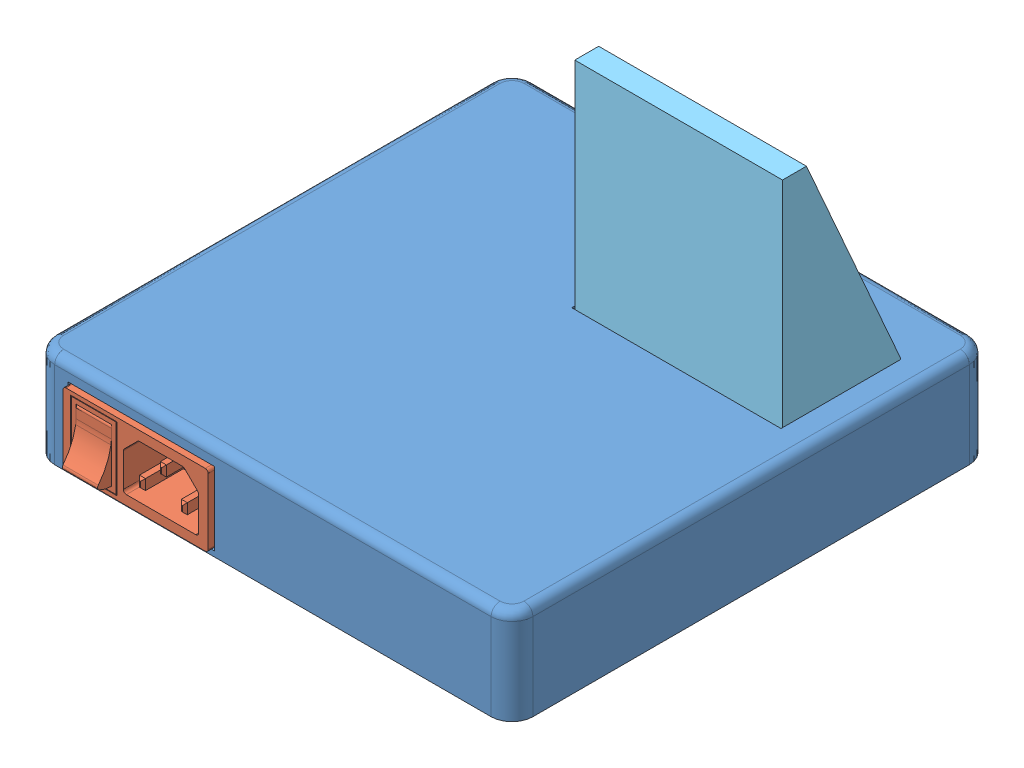
SolidWorks assembly heatplate_case, configuration Default. Lengths in mm.
Overall size (160 104.21 166.72).
6 component instances, 6 part files, 12 mates.
Components (placement in the parent):
- case-2: case [Default] at (15.3311 -15.6956 -180.8) size (160 32 160)
- IEC-socket+switch-2: IEC-socket+switch [Default] at (-13.1856 2.06 -57.9) x (1 0 0) z (0 0 -1) size (48.6 24 24.72)
- SSR40-2: SSR40 [Default] at (-9.1885 -15.6956 -131.0539) size (60 23 46)
- PSU_5V-3: PSU_5V [Default] at (65.283 -13.6956 -117.2434) size (74.5 28 51)
- case-display-holder-1: case-display-holder [Default] at (69.23 16.7044 -176.9583) x (1 0 0) z (0 0 -1) size (75.5 78.76 60)
- LCD-1: LCD [Default] at (81.3746 13.3913 -195.3412) x (-1 0 0) z (0 0.403846 -0.914827) size (63.15 82.2 5.6)
Mates (geometry in assembly coordinates):
- Coincident1: coincident anti-aligned: plane of case-2 through (95.2644 14.3044 -61.5) normal (0 0 1); plane of IEC-socket+switch-2 through (-2.2597 -12.4456 -61.5) normal (0 0 -1)
- Coincident3: coincident anti-aligned: plane of case-2 through (-50.2597 10.5544 -117.7837) normal (0 -1 0); plane of IEC-socket+switch-2 through (-48.8597 10.5544 -61.5) normal (0 1 0)
- Coincident4: coincident anti-aligned: plane of case-2 through (-1.2597 10.5544 -117.7837) normal (-1 0 0); plane of IEC-socket+switch-2 through (-1.2597 -12.4456 -61.5) normal (1 0 0)
- Coincident5: coincident aligned: plane of case-2 through (15.3311 -15.6956 -180.8) normal (0 -1 0); plane of PSU_5V-2 through (1656.1127 -15.6956 878.9867) normal (0 -1 0)
- Coincident6: coincident aligned: plane of case-2 through (15.3311 -15.6956 -180.8) normal (0 -1 0); plane of SSR40-2 through (-9.1885 -15.6956 -131.0539) normal (0 -1 0)
- Coincident8: coincident anti-aligned: plane of case-2 through (15.3311 14.3044 -180.8) normal (0 -1 0); plane of PSU_5V-3 through (65.283 14.3044 -117.2434) normal (0 1 0)
- Coincident11: coincident anti-aligned: plane of case-2 through (15.3311 11.3044 -180.8) normal (0 -1 0); plane of case-display-holder-1 through (69.23 11.3044 -176.9583) normal (0 1 0)
- Coincident13: coincident anti-aligned: plane of case-2 through (88.2644 -15.6966 -200) normal (-1 0 0); plane of case-display-holder-1 through (88.2644 15.7044 -160.5) normal (1 0 0)
- Coincident14: coincident anti-aligned: plane of case-2 through (18.2644 -15.6966 -200) normal (0 0 1); plane of case-display-holder-1 through (18.7644 15.7044 -200) normal (0 0 -1)
- Coincident15: coincident aligned: plane of case-display-holder-1 through (4.7046 88.0609 -168.5) normal (0 0.403846 -0.914827); plane of LCD-1 through (81.3746 15.6528 -200.4642) normal (0 0.403846 -0.914827)
- Parallel2: parallel anti-aligned: plane of case-display-holder-1 through (86.2644 9.3034 -162.5) normal (-1 0 0); plane of LCD-1 through (78.9144 82.1064 -171.1286) normal (1 0 0)
- Distance2: distance = 7.35 mm anti-aligned: plane of LCD-1 through (78.9144 82.1064 -171.1286) normal (1 0 0); plane of case-display-holder-1 through (86.2644 9.3034 -162.5) normal (-1 0 0)
